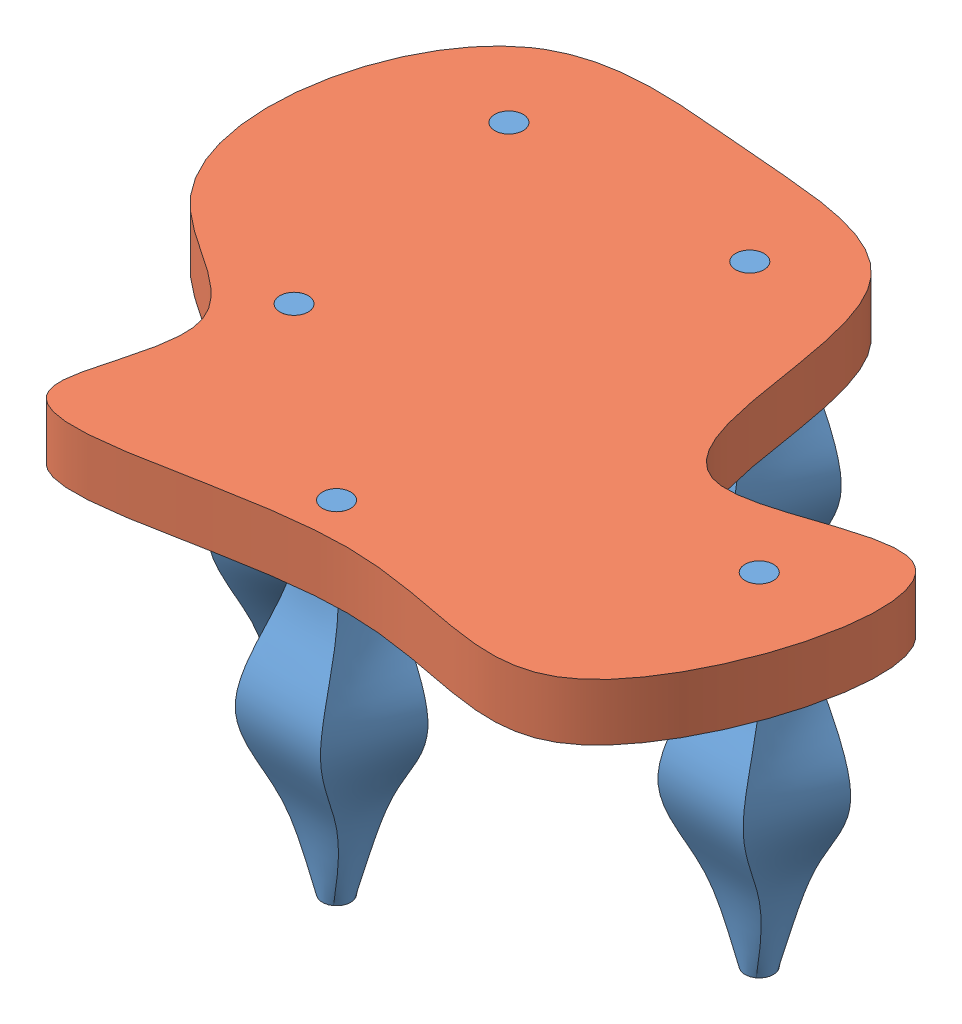
SolidWorks assembly Fancy Table, configuration Default. Lengths in mm.
Overall size (132.4 60 104.54).
6 component instances, 2 part files, 5 mates.
Components (placement in the parent):
- Fancy Table Leg-1: Fancy Table Leg [Default] at (-4.8284 4.8219 78.422) x (0.662895 0 0.748713) z (-0.748713 0 0.662895) size (33.75 60 31.85)
- Fancy Table Top-1: Fancy Table Top [Default] at (4.9295 54.8219 68.4566) size (132.4 10 103.36)
- Fancy Table Leg-2: Fancy Table Leg [Default] at (76.9714 4.8219 78.422) size (33.75 60 31.85)
- Fancy Table Leg-3: Fancy Table Leg [Default] at (28.8051 4.8219 104.5814) size (33.75 60 31.85)
- Fancy Table Leg-4: Fancy Table Leg [Default] at (-13.5481 4.8219 31.9166) size (33.75 60 31.85)
- Fancy Table Leg-5: Fancy Table Leg [Default] at (28.8051 4.8219 31.9166) size (33.75 60 31.85)
Mates (geometry in assembly coordinates):
- Coincident1: coincident aligned: circle of Fancy Table Leg-1; circle of Fancy Table Top-1
- Coincident2: coincident aligned: circle of Fancy Table Top-1; circle of Fancy Table Leg-3
- Coincident3: coincident aligned: circle of Fancy Table Top-1; circle of Fancy Table Leg-2
- Coincident4: coincident aligned: circle of Fancy Table Top-1; circle of Fancy Table Leg-4
- Coincident5: coincident aligned: circle of Fancy Table Top-1; circle of Fancy Table Leg-5
